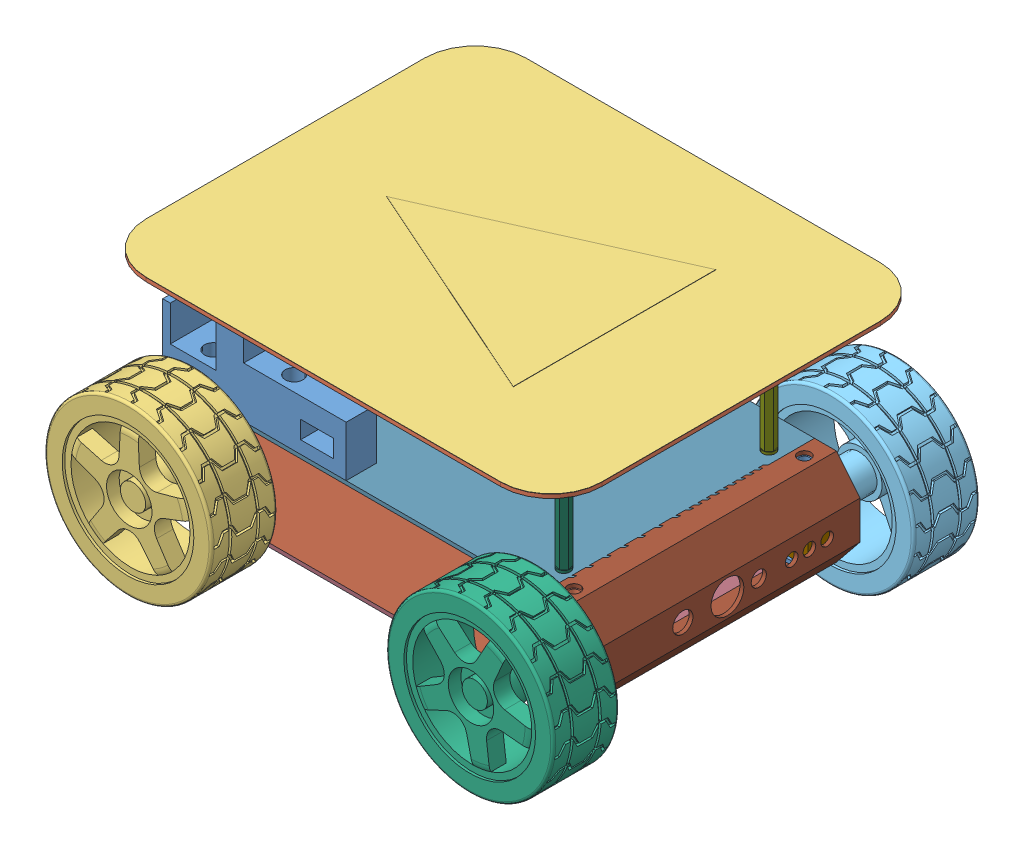
SolidWorks assembly UGV, configuration Predeterminado. Lengths in mm.
Overall size (222.32 114.9 168.4).
21 component instances, 21 part files, 51 mates.
Components (placement in the parent):
- Right_side-1: Right_side [Predeterminado] at (-79.8994 -8.3264 43.1459) size (165 35 11.5)
- Left_side-1: Left_side [Predeterminado] at (-7.6695 -8.3264 150.1459) x (-1 0 0) z (0 0 -1) size (165 35 11.5)
- Tyre_1-1: Tyre_1 [Predeterminado] at (-111.2844 0.9805 154.8459) size (66 66.1 30.7)
- Tyre_2-1: Tyre_2 [Predeterminado] at (-111.2844 0.9805 38.4459) x (0.923728 0.383049 0) z (0 0 -1) size (66 66.1 30.7)
- Tyre_3-1: Tyre_3 [Predeterminado] at (23.7156 0.9805 38.4459) x (0.923728 0.383049 0) z (0 0 -1) size (66 66.1 30.7)
- Tyre_4-1: Tyre_4 [Predeterminado] at (23.7156 0.9805 154.8459) x (0.897882 -0.440236 0) z (0 0 1) size (66 66.1 30.7)
- Engine_1-1: Engine_1 [Predeterminado] at (-95.1598 -0.5607 148.6459) x (0 1 0) z (0 0 -1) size (23 48 47.5)
- Engine_2-1: Engine_2 [Predeterminado] at (7.5909 2.5217 148.6459) x (0 -1 0) z (0 0 -1) size (23 48 47.5)
- Engine_3-1: Engine_3 [Predeterminado] at (7.5909 -0.5607 44.6459) x (0 1 0) z (0 0 1) size (23 48 47.5)
- Engine_4-1: Engine_4 [Predeterminado] at (-95.1598 2.5217 44.6459) x (0 -1 0) z (0 0 1) size (23 48 47.5)
- Back_bumper-2: Back_bumper [Predeterminado] at (21.2156 -16.5195 43.1459) size (19 38 107)
- Front_bumper-1: Front_bumper [Predeterminado] at (-108.7844 -16.5195 150.1459) x (-1 0 0) z (0 0 -1) size (19 38 107)
- Base-1: Base [Predeterminado] at (-33.82 -18.0195 113.5866) x (-1 0 0) z (0 1 0) size (131 107 1.5)
- Top_box-1: Top_box [Predeterminado] at (-53.7489 18.4805 79.7052) x (1 0 0) z (0 1 0) size (131 107 1.5)
- Separator_Top_UGV_1-1: Separator_Top_UGV_1 [Predeterminado] at (20.6813 19.9805 141.6232) x (1 0 0) z (0 1 0) size (5 5 50)
- Separator_Top_UGV_2-1: Separator_Top_UGV_2 [Predeterminado] at (20.6813 19.9805 60.6232) x (1 0 0) z (0 1 0) size (5 5 50)
- Separator_Top_UGV_3-1: Separator_Top_UGV_3 [Predeterminado] at (-100.3187 19.9805 141.6232) x (1 0 0) z (0 1 0) size (5 5 50)
- Separator_Top_UGV_4-1: Separator_Top_UGV_4 [Predeterminado] at (-100.3187 19.9805 60.6232) x (1 0 0) z (0 1 0) size (5 5 50)
- Battery_and_Charger_support-1: Battery_and_Charger_support [Predeterminado] at (-128.2844 19.9805 43.1459) size (72.5 45 107)
- Top_UGV-2: Top_UGV [Predeterminado] at (-58.5448 69.9805 103.9376) x (0 0 -1) z (0 1 0) size (150 180 1.5)
- Positioning_arrow-1: Positioning_arrow [Predeterminado] at (-58.5448 71.4805 103.9376) x (0 0 -1) z (0 1 0) size (150 180 0.2)
Mates (geometry in assembly coordinates):
- Concéntrica3: concentric anti-aligned: cylinder of Left_side-1 through (-111.2844 0.9805 150.1469) axis (0 0 -1) radius 4; cylinder of Tyre_1-1 through (-111.2844 0.9805 178.8459) axis (0 0 1) radius 7
- Coincidente9: coincident anti-aligned: plane of Left_side-1 through (-7.6695 -8.3264 150.1459) normal (0 0 1); plane of Tyre_1-1 through (-111.2844 0.9805 150.1459) normal (0 0 -1)
- Concéntrica4: concentric anti-aligned: cylinder of Left_side-1 through (23.7156 0.9805 150.1469) axis (0 0 -1) radius 4; cylinder of Tyre_4-1 through (23.7156 0.9805 178.8459) axis (0 0 1) radius 7
- Coincidente10: coincident anti-aligned: plane of Left_side-1 through (-7.6695 -8.3264 150.1459) normal (0 0 1); plane of Tyre_4-1 through (23.7156 0.9805 150.1459) normal (0 0 -1)
- Concéntrica5: concentric anti-aligned: cylinder of Right_side-1 through (23.7156 0.9805 43.1449) axis (0 0 1) radius 4; cylinder of Tyre_3-1 through (23.7156 0.9805 14.4459) axis (0 0 -1) radius 7
- Coincidente11: coincident anti-aligned: plane of Right_side-1 through (-79.8994 -8.3264 43.1459) normal (0 0 -1); plane of Tyre_3-1 through (23.7156 0.9805 43.1459) normal (0 0 1)
- Concéntrica6: concentric anti-aligned: cylinder of Right_side-1 through (-111.2844 0.9805 43.1449) axis (0 0 1) radius 4; cylinder of Tyre_2-1 through (-111.2844 0.9805 14.4459) axis (0 0 -1) radius 7
- Coincidente12: coincident anti-aligned: plane of Right_side-1 through (-79.8994 -8.3264 43.1459) normal (0 0 -1); plane of Tyre_2-1 through (-111.2844 0.9805 43.1459) normal (0 0 1)
- Concéntrica7: concentric aligned: cylinder of Left_side-1 through (-111.2844 0.9805 150.1469) axis (0 0 -1) radius 4; cylinder of Engine_1-1 through (-111.2844 0.9805 149.6459) axis (0 0 -1) radius 2
- Coincidente19: coincident anti-aligned: plane of Left_side-1 through (-7.6695 -8.3264 148.6459) normal (0 0 -1); plane of Engine_1-1 through (-95.1598 -0.5607 148.6459) normal (0 0 1)
- Paralelo1: parallel anti-aligned: plane of Left_side-1 through (30.2156 16.9805 138.6459) normal (0 -1 0); plane of Engine_1-1 through (-122.2844 12.4805 135.1459) normal (0 1 0)
- Concéntrica8: concentric aligned: cylinder of Left_side-1 through (23.7156 0.9805 150.1469) axis (0 0 -1) radius 4; cylinder of Engine_2-1 through (23.7156 0.9805 149.6459) axis (0 0 -1) radius 2
- Coincidente21: coincident anti-aligned: plane of Left_side-1 through (-7.6695 -8.3264 148.6459) normal (0 0 -1); plane of Engine_2-1 through (7.5909 2.5217 148.6459) normal (0 0 1)
- Paralelo2: parallel anti-aligned: plane of Left_side-1 through (30.2156 16.9805 138.6459) normal (0 -1 0); plane of Engine_2-1 through (-7.2844 12.4805 135.1459) normal (0 1 0)
- Concéntrica9: concentric aligned: cylinder of Right_side-1 through (23.7156 0.9805 43.1449) axis (0 0 1) radius 4; cylinder of Engine_3-1 through (23.7156 0.9805 43.6459) axis (0 0 1) radius 2
- Coincidente23: coincident anti-aligned: plane of Right_side-1 through (-79.8994 -8.3264 44.6459) normal (0 0 1); plane of Engine_3-1 through (7.5909 -0.5607 44.6459) normal (0 0 -1)
- Paralelo3: parallel anti-aligned: plane of Right_side-1 through (-117.7844 -15.0195 54.6459) normal (0 1 0); plane of Engine_3-1 through (-7.2844 -10.5195 58.1459) normal (0 -1 0)
- Concéntrica10: concentric aligned: cylinder of Right_side-1 through (-111.2844 0.9805 43.1449) axis (0 0 1) radius 4; cylinder of Engine_4-1 through (-111.2844 0.9805 43.6459) axis (0 0 1) radius 2
- Coincidente25: coincident anti-aligned: plane of Right_side-1 through (-79.8994 -8.3264 44.6459) normal (0 0 1); plane of Engine_4-1 through (-95.1598 2.5217 44.6459) normal (0 0 -1)
- Paralelo4: parallel anti-aligned: plane of Right_side-1 through (-117.7844 16.9805 54.6459) normal (0 -1 0); plane of Engine_4-1 through (-80.2844 12.4805 58.1459) normal (0 1 0)
- Concéntrica14: concentric aligned: circle of Left_side-1; circle of Back_bumper-2
- Coincidente28: coincident anti-aligned: plane of Right_side-1 through (-117.7844 18.4805 44.6459) normal (0 1 0); plane of Back_bumper-2 through (21.2156 18.4805 150.1459) normal (0 -1 0)
- Concéntrica16: concentric aligned: circle of Left_side-1; circle of Front_bumper-1
- Coincidente32: coincident anti-aligned: plane of Left_side-1 through (30.2156 18.4805 148.6459) normal (0 1 0); plane of Front_bumper-1 through (-108.7844 18.4805 43.1459) normal (0 -1 0)
- Coincidente33: coincident anti-aligned: plane of Right_side-1 through (-126.2844 7.9805 44.6459) normal (-1 0 0); plane of Front_bumper-1 through (-126.2844 -6.0195 43.1459) normal (1 0 0)
- Concéntrica19: concentric aligned: circle of Right_side-1; circle of Front_bumper-1
- Coincidente48: coincident anti-aligned: plane of Right_side-1 through (-117.7844 -16.5195 44.6459) normal (0 -1 0); plane of Base-1 through (-33.82 -16.5195 113.5866) normal (0 1 0)
- Paralelo8: parallel anti-aligned: plane of Front_bumper-1 through (-108.7844 -16.5195 43.1459) normal (1 0 0); plane of Base-1 through (-109.7844 -16.5195 150.1459) normal (-1 0 0)
- Coincidente51: coincident aligned: plane of Left_side-1 through (-7.6695 -8.3264 150.1459) normal (0 0 1); plane of Base-1 through (21.2156 -16.5195 150.1459) normal (0 0 1)
- Coincidente52: coincident anti-aligned: plane of Back_bumper-2 through (21.2156 -16.5195 150.1459) normal (-1 0 0); plane of Base-1 through (21.2156 -16.5195 150.1459) normal (1 0 0)
- Coincidente57: coincident anti-aligned: plane of Left_side-1 through (30.2156 18.4805 148.6459) normal (0 1 0); plane of Top_box-1 through (-53.7489 18.4805 79.7052) normal (0 -1 0)
- Coincidente60: coincident anti-aligned: plane of Front_bumper-1 through (-108.7844 19.9805 43.1459) normal (1 0 0); plane of Top_box-1 through (-108.7844 19.9805 43.1459) normal (-1 0 0)
- Coincidente61: coincident aligned: plane of Right_side-1 through (-79.8994 -8.3264 43.1459) normal (0 0 -1); plane of Top_box-1 through (-108.7844 19.9805 43.1459) normal (0 0 -1)
- Coincidente84: coincident anti-aligned: plane of Right_side-1 through (-117.7844 18.4805 44.6459) normal (0 1 0); plane of Top_box-1 through (-53.7489 18.4805 79.7052) normal (0 -1 0)
- Coincidente85: coincident anti-aligned: plane of Top_box-1 through (-53.7489 19.9805 79.7052) normal (0 1 0); plane of Separator_Top_UGV_4-1 through (-103.7844 19.9805 56.1459) normal (0 -1 0)
- Coincidente86: coincident aligned: circle of Top_box-1; circle of Separator_Top_UGV_4-1
- Coincidente87: coincident anti-aligned: plane of Top_box-1 through (-53.7489 19.9805 79.7052) normal (0 1 0); plane of Separator_Top_UGV_2-1 through (17.2156 19.9805 56.1459) normal (0 -1 0)
- Coincidente88: coincident aligned: circle of Top_box-1; circle of Separator_Top_UGV_2-1
- Coincidente89: coincident anti-aligned: plane of Top_box-1 through (-53.7489 19.9805 79.7052) normal (0 1 0); plane of Separator_Top_UGV_1-1 through (17.2156 19.9805 137.1459) normal (0 -1 0)
- Coincidente90: coincident anti-aligned: plane of Top_box-1 through (-53.7489 19.9805 79.7052) normal (0 1 0); plane of Separator_Top_UGV_3-1 through (-103.7844 19.9805 137.1459) normal (0 -1 0)
- Coincidente91: coincident aligned: circle of Top_box-1; circle of Separator_Top_UGV_1-1
- Coincidente92: coincident aligned: circle of Top_box-1; circle of Separator_Top_UGV_3-1
- Paralelo9: parallel anti-aligned: plane of Top_box-1 through (-53.7489 19.9805 79.7052) normal (0 1 0); plane of Top_UGV-2 through (-113.2844 69.9805 151.6459) normal (0 -1 0)
- Coincidente94: coincident anti-aligned: plane of Separator_Top_UGV_1-1 through (20.6813 69.9805 141.6232) normal (0 1 0); plane of Top_UGV-2 through (-113.2844 69.9805 151.6459) normal (0 -1 0)
- Concéntrica20: concentric anti-aligned: circle of Separator_Top_UGV_1-1; circle of Top_UGV-2
- Paralelo10: parallel aligned: plane of Left_side-1 through (-7.6695 -8.3264 150.1459) normal (0 0 1); plane of Top_UGV-2 through (-113.2844 71.4805 171.6459) normal (0 0 1)
- Coincidente96: coincident anti-aligned: plane of Top_UGV-2 through (-113.2844 71.4805 151.6459) normal (0 1 0); plane of Positioning_arrow-1 through (-113.2844 71.4805 151.6459) normal (0 -1 0)
- Coincidente98: coincident aligned: plane of Top_UGV-2 through (-133.2844 71.4805 151.6459) normal (-1 0 0); plane of Positioning_arrow-1 through (-133.2844 71.5805 151.6459) normal (-1 0 0)
- Coincidente99: coincident aligned: plane of Top_UGV-2 through (-113.2844 71.4805 171.6459) normal (0 0 1); plane of Positioning_arrow-1 through (-113.2844 71.5805 171.6459) normal (0 0 1)
- Concéntrica21: concentric aligned: circle of Separator_Top_UGV_3-1; circle of Battery_and_Charger_support-1
- Coincidente101: coincident anti-aligned: plane of Top_box-1 through (-53.7489 19.9805 79.7052) normal (0 1 0); plane of Battery_and_Charger_support-1 through (-128.2844 19.9805 150.1459) normal (0 -1 0)
